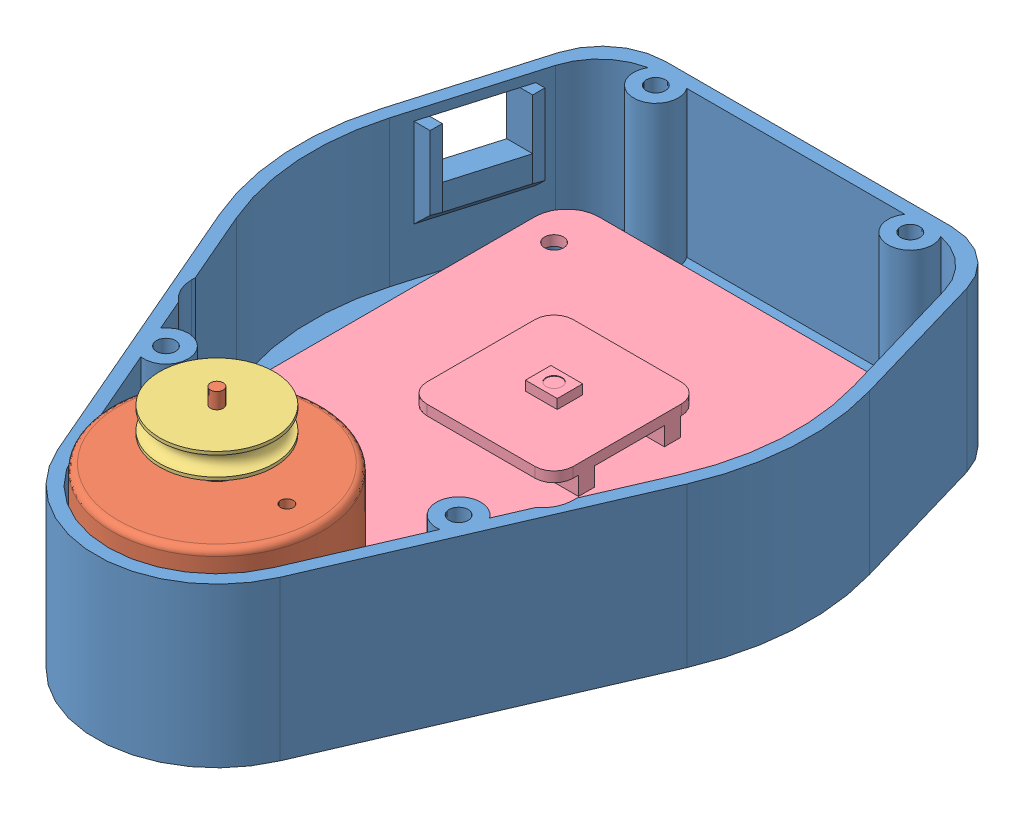
SolidWorks assembly LidarBeta, configuration Default. Lengths in mm.
Overall size (80 70.71 112).
15 component instances, 13 part files, 23 mates.
Components (placement in the parent):
- Cover_base-1: Cover_base [Default] at origin size (80 25 112)
- Cover_top-1: Cover_top [Default] at origin size (80 8 112) (hidden)
- Head_base-1: Head_base [Default] at (0 37.0834 0) x (-0.258111 0 0.966115) z (-0.966115 0 -0.258111) size (70 58 70) (hidden)
- Head_top-1: Head_top [Default] at (0 15.2712 0) x (0.966115 0 0.258111) z (-0.258111 0 0.966115) size (70 39 70) (hidden)
- 6810-1: 6810 [Default] at (0 40.5782 0) x (0 1 0) z (0.911895 0 -0.410424) size (7.01 65 65) (hidden)
- RF-530-1: RF-530 [Default] at (0 22.073 53) size (33 31.5 33)
- Pulley-1: Pulley [Default] at (0 -2.4896 0) size (18 4 18)
- Slipring_v1.1-1: Slipring_v1.1 [Default] at (0 46.0834 0) x (-0.672958 0 -0.739681) z (-0.739681 0 0.672958) size (22 17 22) (hidden)
- Lidar_PCB-1: Lidar_PCB [Default] at (0 17.073 0) x (0 0 1) z (-1 0 0) size (64 7.6 60)
- Lidar_Lite_V2-1: Lidar_Lite_V2 [Default] at (-19.3223 65.0834 -5.1622) x (0.258111 0 -0.966115) z (0.966115 0 0.258111) size (48 35.4 39.5) (hidden)
  - Garmin_Lidar_Lite_3.step-1: Garmin_Lidar_Lite_3.step [Default] at origin size (48 35.4 39.5)
    - Garmin_Lidar_Lite_31.step-1: Garmin_Lidar_Lite_31.step [Default] at origin size (48 35.4 5)
    - Garmin_Lidar_Lite_32.step-1: Garmin_Lidar_Lite_32.step [Default] at origin size (48 20 37)
    - Garmin_Lidar_Lite_33.step-1: Garmin_Lidar_Lite_33.step [Default] at origin size (12.5 4.5 2)
    - Garmin_Lidar_Lite_34.step-1: Garmin_Lidar_Lite_34.step [Default] at origin size (10.35 3.3 4.35)
Mates (geometry in assembly coordinates):
- Coincident2: coincident anti-aligned: plane of Cover_base-1 through (-22.5 37.073 -30) normal (0 1 0); plane of Cover_top-1 through (0 37.073 0) normal (0 -1 0)
- Concentric2: concentric aligned: cylinder of Cover_base-1 through (-23 32.073 38) axis (0 1 0) radius 1.5; cylinder of Cover_top-1 through (-23 40.073 38) axis (0 1 0) radius 3
- Concentric3: concentric aligned: cylinder of Cover_base-1 through (23 32.073 38) axis (0 1 0) radius 1.5; cylinder of Cover_top-1 through (23 40.073 38) axis (0 1 0) radius 3
- Concentric4: concentric aligned: cylinder of Cover_top-1 through (0 44.073 0) axis (0 -1 0) radius 32.5; cylinder of 6810-1 through (0 36.7225 0) axis (0 -1 0) radius 32.4993
- Coincident3: coincident anti-aligned: plane of Cover_top-1 through (0 37.073 0) normal (0 1 0); plane of 6810-1 through (0 37.073 0) normal (0 -1 0)
- Concentric5: concentric aligned: circle of 6810-1; cylinder of Head_base-1 through (0 47.0834 0) axis (0 -1 0) radius 35
- Coincident4: coincident anti-aligned: plane of 6810-1 through (0 44.0834 0) normal (0 1 0); plane of Head_base-1 through (0 44.0834 0) normal (0 -1 0)
- Concentric6: concentric aligned: cylinder of Head_base-1 through (0 47.0834 0) axis (0 -1 0) radius 35; cylinder of Head_top-1 through (0 189.0784 0) axis (0 -1 0) radius 35
- Coincident5: coincident anti-aligned: plane of Head_base-1 through (-19.3223 37.0834 -5.1622) normal (0.966115 0 0.258111); plane of ? through (-19.3223 65.0834 -5.1622) normal (-0.966115 0 -0.258111)
- Coincident6: coincident anti-aligned: plane of Head_base-1 through (0 47.0834 0) normal (0 1 0); plane of Head_top-1 through (0 47.0834 0) normal (0 -1 0)
- Concentric10: concentric anti-aligned: cylinder of Cover_top-1 through (0 34.073 53) axis (0 1 0) radius 3.5; cylinder of RF-530-1 through (0 41.573 53) axis (0 -1 0) radius 3.5
- Coincident7: coincident anti-aligned: circle of Cover_top-1; plane of RF-530-1 through (0 40.073 53) normal (0 1 0)
- Concentric11: concentric aligned: cylinder of Cover_top-1 through (-11 34.073 53) axis (0 1 0) radius 1; cylinder of RF-530-1 through (-11 38.573 53) axis (0 1 0) radius 1
- Concentric12: concentric anti-aligned: cylinder of RF-530-1 through (0 50.573 53) axis (0 -1 0) radius 1; cylinder of Pulley-1 through (0 44.0834 53) axis (0 1 0) radius 1
- Coincident8: coincident aligned: circle of Head_top-1; plane of Pulley-1 through (0 48.0834 53) normal (0 1 0)
- Concentric13: concentric anti-aligned: cylinder of Head_base-1 through (0 45.0834 0) axis (0 -1 0) radius 11.3; cylinder of Slipring_v1.1-1 through (0 30.0834 0) axis (0 1 0) radius 11
- Coincident9: coincident anti-aligned: plane of Head_base-1 through (0 30.0834 0) normal (0 1 0); plane of Slipring_v1.1-1 through (0 30.0834 0) normal (0 -1 0)
- Concentric15: concentric aligned: cylinder of Head_base-1 through (-18.5168 78.9334 -19.8003) axis (0.966115 0 0.258111) radius 1.5; cylinder of ? through (-15.6184 78.9334 -19.026) axis (0.966115 0 0.258111) radius 1.85
- Concentric16: concentric anti-aligned: cylinder of Head_base-1 through (24.1529 64.0834 6.4528) axis (0 -1 0) radius 1.5; cylinder of Head_top-1 through (24.1529 71.0834 6.4528) axis (0 1 0) radius 3
- Concentric17: concentric aligned: cylinder of Head_top-1 through (37.5566 65.0834 -4.9748) axis (-0.966115 0 -0.258111) radius 8; cylinder of ? through (22.5819 65.0834 -8.9755) axis (-0.966115 0 -0.258111) radius 7.5
- Coincident10: coincident anti-aligned: plane of Cover_base-1 through (25 17.073 25) normal (0 1 0); plane of Lidar_PCB-1 through (-25 17.073 -27) normal (0 -1 0)
- Concentric18: concentric aligned: cylinder of Cover_base-1 through (-25 17.073 -25) axis (0 -1 0) radius 1.5; cylinder of Lidar_PCB-1 through (-25 18.673 -25) axis (0 -1 0) radius 1.5
- Concentric19: concentric aligned: cylinder of Cover_base-1 through (25 17.073 25) axis (0 -1 0) radius 1.5; cylinder of Lidar_PCB-1 through (25 18.673 25) axis (0 -1 0) radius 1.5
